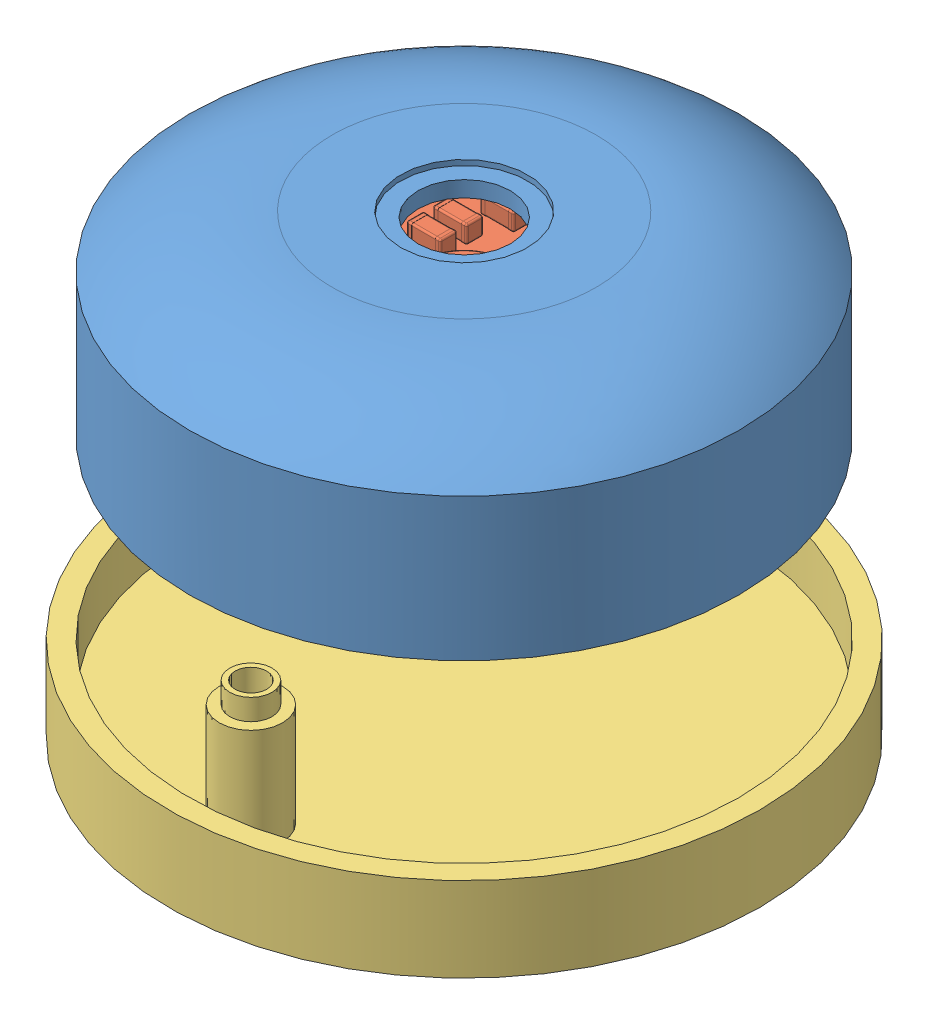
SolidWorks assembly Enclosure1_1, configuration Default. Lengths in mm.
Overall size (56 55.73 56).
4 component instances, 3 part files, 4 mates.
Components (placement in the parent):
- EnclosureTop-1: EnclosureTop [Default] at origin size (53 31.11 53)
- Candunio-1: Candunio [Default] at (0 -5.0974 0) x (-1 0 0) z (0 -1 0) size (46.25 46 13.96)
- Assem1^Enclosure1_1-1: Assem1^Enclosure1_1 [Default] at (0 3.4017 0) size (56 14.75 56) (virtual)
  - EnclosureBottom-1: EnclosureBottom [Default] at (0 -41.5222 0) x (0 0 1) z (-1 0 0) size (56 14.75 56)
Mates (geometry in assembly coordinates):
- Concentric13: concentric: circle of EnclosureTop-1; circle of Candunio-1
- Concentric17: concentric: cylinder of EnclosureTop-1 through (0 -1.65 -20.2) axis (0 -1 0) radius 1.25; circle of Assem1^Enclosure1_1-1/EnclosureBottom-1
- Concentric18: concentric: cylinder of EnclosureTop-1 through (0 -1.65 20.2) axis (0 -1 0) radius 1.25; circle of Assem1^Enclosure1_1-1/EnclosureBottom-1
- Concentric19: concentric: circle of Candunio-1; circle of Assem1^Enclosure1_1-1/EnclosureBottom-1
